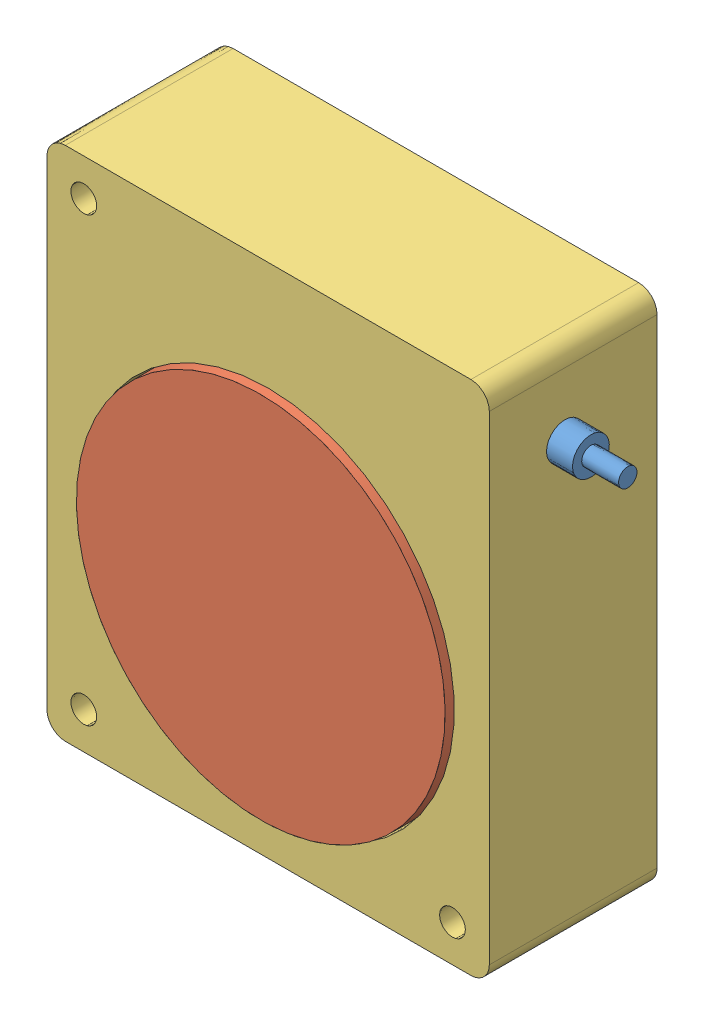
SolidWorks assembly Assem rotary, configuration Default. Lengths in mm.
Overall size (147.55 151.44 48.25).
4 component instances, 4 part files, 9 mates.
Components (placement in the parent):
- worm-1: worm [Default] at (-42.9531 57.8087 0) x (1 0 0) z (0 -0.541845 0.840478) size (120 33.13 33.98)
- worm wheel-1: worm wheel [Default] at (0 0 -17.5) x (0.897512 -0.440991 0) z (0 0 1) size (105.35 105.35 40.24)
- Part4^Assem rotary-1: Part4^Assem rotary [Default] at origin (virtual)
- Rotary casing-1: Rotary casing [Default] at (60 -60 -25) x (0 1 0) z (0 0 1) size (140 120 45.5)
Mates (geometry in assembly coordinates):
- Coincident1: coincident: plane of worm wheel-1 through (0 0 0) normal (0 0 -1); plane of assembly through (0 0 0) normal (0 0 1)
- Coincident4: coincident: axis of worm wheel-1 through (0 0 22.5) axis (0 0 -1); point of assembly
- Coincident7: coincident: axis of worm-1 through (22.0469 57.8087 0) axis (1 0 0); plane of assembly
- Distance1: distance = 77.0469 mm: plane of assembly through (0 0 0) normal (1 0 0); plane of worm-1 through (77.0469 59.9099 1.3546) normal (1 0 0)
- Distance2: distance = 57.8087 mm: axis of worm-1 through (-42.9531 57.8087 0) axis (1 0 0); plane of assembly
- GearMate1: gear = 1 : 44 mm: cylinder of worm-1 through (77.0469 57.8087 0) axis (1 0 0) radius 5; cylinder of worm wheel-1 through (0 0 22.5) axis (0 0 -1) radius 50
- Concentric2: concentric: circle of worm wheel-1; circle of Rotary casing-1
- Parallel2: parallel: plane of worm-1 through (77.0469 59.9099 1.3546) normal (1 0 0); plane of Rotary casing-1 through (60 75 20.5) normal (1 0 0)
- Coincident12: coincident: circle of worm wheel-1; circle of Rotary casing-1
